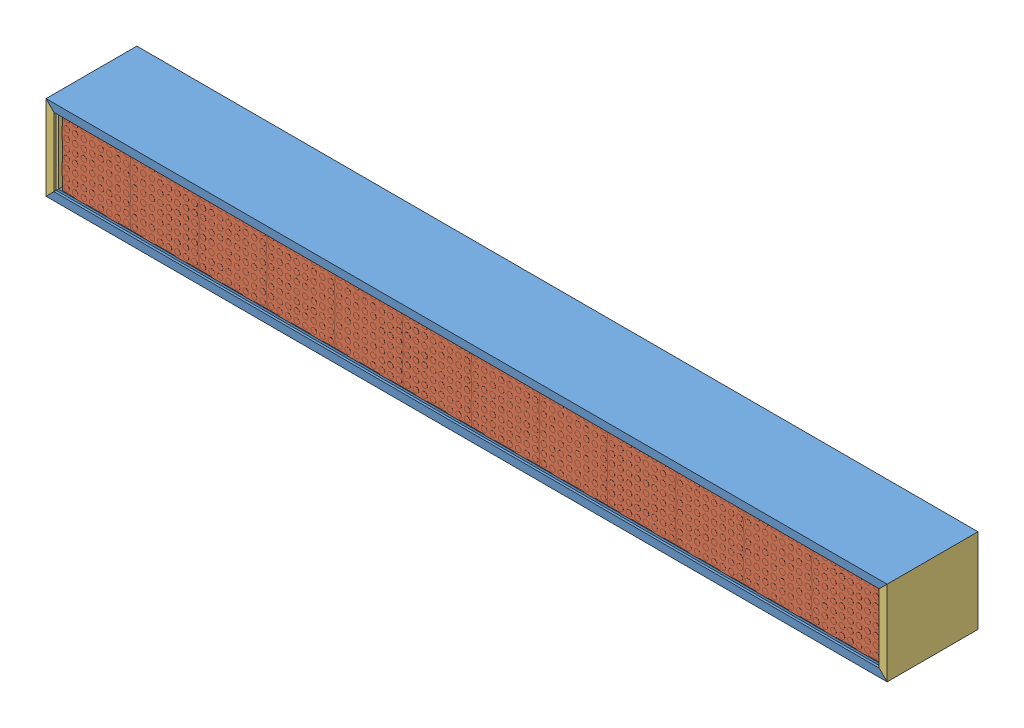
SolidWorks assembly assembly, configuration Default. Lengths in mm.
Overall size (740.5 74.5 80).
16 component instances, 3 part files, 11 mates.
Components (placement in the parent):
- hosszu-1: hosszu [Default] at (412.2916 374.6461 644.0475) size (740.5 10 80)
- hosszu-2: hosszu [Default] at (412.2916 449.1461 644.0475) x (-1 0 0) z (0 0 1) size (740.5 10 80)
- MAX7219_8X8LED_BOARD-1: MAX7219_8X8LED_BOARD [Default] at (57.5415 387.146 673.0475) x (1 0 0) z (0 0 1) size (66.4 60.5 11.27)
- MAX7219_8X8LED_BOARD-2: MAX7219_8X8LED_BOARD [Default] at (117.5415 387.146 673.0475) x (1 0 0) z (0 0 1) size (66.4 60.5 11.27)
- MAX7219_8X8LED_BOARD-3: MAX7219_8X8LED_BOARD [Default] at (177.5415 387.146 673.0475) x (1 0 0) z (0 0 1) size (66.4 60.5 11.27)
- MAX7219_8X8LED_BOARD-4: MAX7219_8X8LED_BOARD [Default] at (237.5415 387.146 673.0475) x (1 0 0) z (0 0 1) size (66.4 60.5 11.27)
- MAX7219_8X8LED_BOARD-5: MAX7219_8X8LED_BOARD [Default] at (297.5415 387.146 673.0475) x (1 0 0) z (0 0 1) size (66.4 60.5 11.27)
- MAX7219_8X8LED_BOARD-6: MAX7219_8X8LED_BOARD [Default] at (357.5415 387.146 673.0475) x (1 0 0) z (0 0 1) size (66.4 60.5 11.27)
- MAX7219_8X8LED_BOARD-7: MAX7219_8X8LED_BOARD [Default] at (417.5415 387.146 673.0475) x (1 0 0) z (0 0 1) size (66.4 60.5 11.27)
- MAX7219_8X8LED_BOARD-8: MAX7219_8X8LED_BOARD [Default] at (477.5415 387.146 673.0475) x (1 0 0) z (0 0 1) size (66.4 60.5 11.27)
- MAX7219_8X8LED_BOARD-9: MAX7219_8X8LED_BOARD [Default] at (537.5415 387.146 673.0475) x (1 0 0) z (0 0 1) size (66.4 60.5 11.27)
- MAX7219_8X8LED_BOARD-10: MAX7219_8X8LED_BOARD [Default] at (597.5415 387.146 673.0475) x (1 0 0) z (0 0 1) size (66.4 60.5 11.27)
- MAX7219_8X8LED_BOARD-11: MAX7219_8X8LED_BOARD [Default] at (657.5415 387.146 673.0475) x (1 0 0) z (0 0 1) size (66.4 60.5 11.27)
- MAX7219_8X8LED_BOARD-12: MAX7219_8X8LED_BOARD [Default] at (717.5415 387.146 673.0475) x (1 0 0) z (0 0 1) size (66.4 60.5 11.27)
- vegek2-1: vegek2 [Default] at (42.0416 411.8961 644.0475) x (0 -1 0) z (0 0 1) size (74.5 10 80)
- vegek2-2: vegek2 [Default] at (782.5416 411.8961 644.0475) x (0 1 0) z (0 0 1) size (74.5 10 80)
Mates (geometry in assembly coordinates):
- Coincident25: coincident aligned: plane of vegek2-1 through (52.0416 449.1461 684.0475) normal (0 0 1); plane of hosszu-1 through (42.0416 384.6461 684.0475) normal (0 0 1)
- Coincident26: coincident aligned: plane of hosszu-1 through (42.0416 384.6461 684.0475) normal (0 0 1); plane of vegek2-2 through (772.5416 374.6461 684.0475) normal (0 0 1)
- Coincident27: coincident aligned: plane of hosszu-1 through (42.0416 384.6461 684.0475) normal (0 0 1); plane of hosszu-2 through (782.5416 439.1461 684.0475) normal (0 0 1)
- Coincident28: coincident anti-aligned: line of hosszu-1 through (42.0416 374.6461 604.0475) axis (0 0 1); line of vegek2-1 through (42.0416 374.6461 684.0475) axis (0 0 -1)
- Coincident29: coincident anti-aligned: line of hosszu-2 through (42.0416 449.1461 684.0475) axis (0 0 -1); line of vegek2-1 through (42.0416 449.1461 604.0475) axis (0 0 1)
- Coincident31: coincident anti-aligned: line of hosszu-2 through (782.5416 449.1461 604.0475) axis (0 0 1); line of vegek2-2 through (782.5416 449.1461 684.0475) axis (0 0 -1)
- Coincident32: coincident anti-aligned: line of hosszu-1 through (782.5416 374.6461 684.0475) axis (0 0 -1); line of vegek2-2 through (782.5416 374.6461 604.0475) axis (0 0 1)
- Coincident35: coincident: point of hosszu-2; point of vegek2-1
- Width1: width aligned: plane of MAX7219_8X8LED_BOARD-12 through (772.5416 382.1461 680.0475) normal (1 0 0); plane of MAX7219_8X8LED_BOARD-1 through (52.0416 412.1461 673.0475) normal (-1 0 0); plane of vegek2-1 through (49.0416 374.6461 684.0475) normal (1 0 0); plane of vegek2-2 through (775.5416 449.1461 684.0475) normal (-1 0 0)
- Coincident37: coincident anti-aligned: plane of hosszu-1 through (782.5416 381.6461 684.0475) normal (0 1 0); plane of MAX7219_8X8LED_BOARD-1 through (82.5416 381.6461 673.0475) normal (0 -1 0)
- Coincident38: coincident anti-aligned: plane of hosszu-2 through (42.0416 439.1461 673.0475) normal (0 0 1); plane of MAX7219_8X8LED_BOARD-1 through (82.5416 412.1461 673.0475) normal (0 0 -1)
